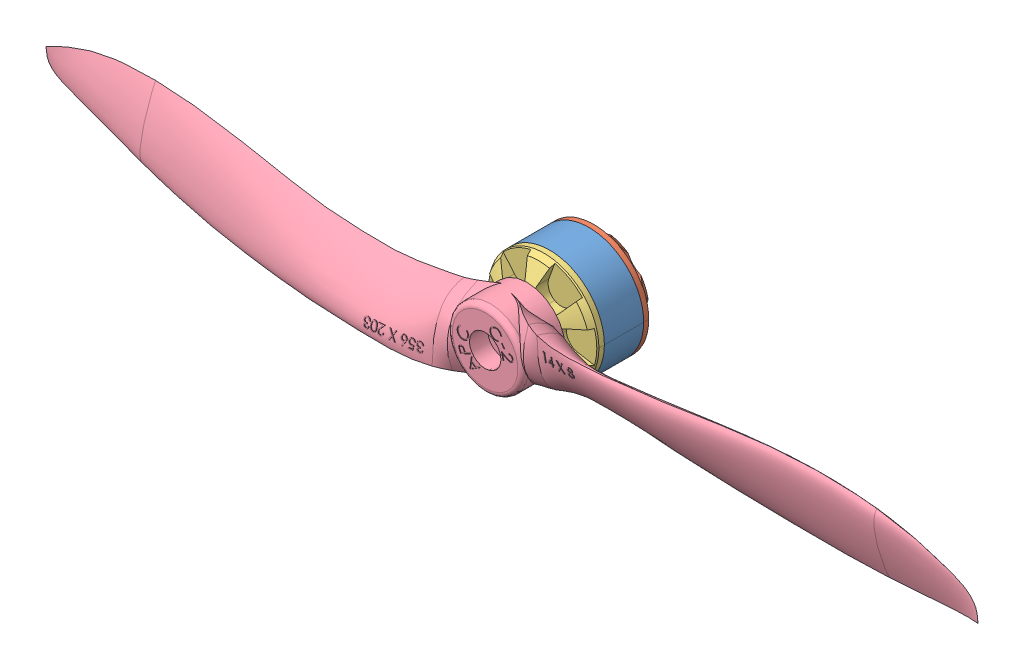
SolidWorks assembly motor + prop, configuration Default. Lengths in mm.
Overall size (355.6 41.8 52.4).
6 component instances, 4 part files, 2 mates.
Components (placement in the parent):
- T Motor MN3510-1: T Motor MN3510 [Default] at (6.5074 22.0096 18.2014) size (41.8 41.8 37.1)
  - assembly_drone-Modelmotor_thrust001.step-1: assembly_drone-Modelmotor_thrust001.step [Default] at origin size (41.8 41.8 37.1)
    - Component3.step.step-1: Component3.step.step [Default] at origin size (41.8 41.8 15)
    - Component1.step.step-1: Component1.step.step [Default] at origin size (41.8 41.8 7.52)
    - Component2.step.step-1: Component2.step.step [Default] at origin size (41.8 41.8 14.58)
- APC Prop 14x8-1: APC Prop 14x8 [Valor predeterminado] at (6.5074 22.0096 49.3014) x (1 0 0) z (0 -1 0) size (355.6 22.58 35.02)
Mates (geometry in assembly coordinates):
- Coincident1: coincident: plane of T Motor MN3510-1/assembly_drone-Modelmotor_thrust001.step-1/Component2.step.step-1 through (6.5074 22.0096 49.3014) normal (0 0 1); plane of APC Prop 14x8-1 through (21.0074 22.0096 49.3014) normal (0 0 -1)
- Concentric1: concentric aligned: cylinder of T Motor MN3510-1/assembly_drone-Modelmotor_thrust001.step-1/Component2.step.step-1 through (6.5074 22.0096 55.3014) axis (0 0 -1) radius 2; cylinder of APC Prop 14x8-1 through (6.5074 22.0096 49.3014) axis (0 0 -1) radius 4
